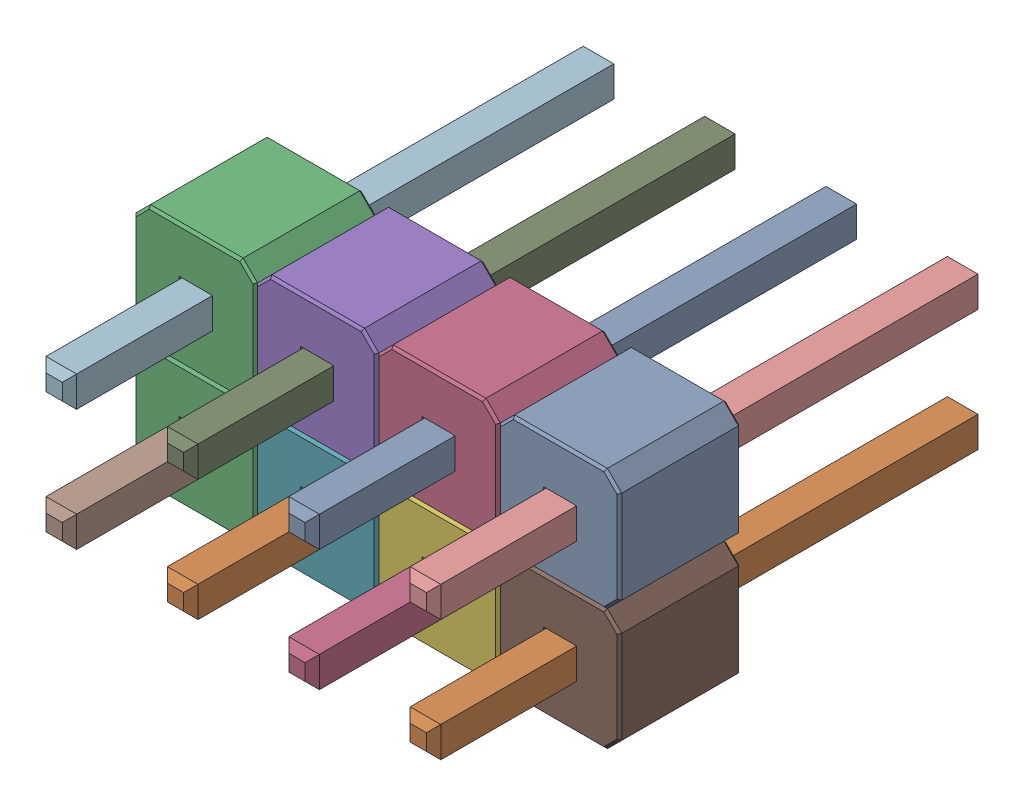
SolidWorks assembly X1_XLR4, configuration Default. Lengths in mm.
Overall size (10.16 5.08 11.54).
17 component instances, 2 part files, 0 mates.
Components (placement in the parent):
- PLD-8-1: PLD-8 [Default] at (47.6251 88.0109 -1.2114) x (1 0 0) z (0 0 -1) size (10.16 5.08 11.54)
  - _______________________-1: _______________________ [Default] at (-2.54 0 -3) size (0.64 0.64 11.54)
  - _______________________-2: _______________________ [Default] at (-5.08 2.54 -3) size (0.64 0.64 11.54)
  - _________-1: _________ [Default] at (-7.6724 2.5342 -0.0112) size (2.54 2.54 2.54)
  - _______________________-3: _______________________ [Default] at (-2.54 2.54 -3) size (0.64 0.64 11.54)
  - _________-2: _________ [Default] at (-5.1324 -0.0058 -0.0112) size (2.54 2.54 2.54)
  - _________-3: _________ [Default] at (-2.5924 2.5342 -0.0112) size (2.54 2.54 2.54)
  - _________-4: _________ [Default] at (-5.1324 2.5342 -0.0112) size (2.54 2.54 2.54)
  - _______________________-4: _______________________ [Default] at (-7.62 2.54 -3) size (0.64 0.64 11.54)
  - _______________________-5: _______________________ [Default] at (-5.08 0 -3) size (0.64 0.64 11.54)
  - _______________________-6: _______________________ [Default] at (0 0 -3) size (0.64 0.64 11.54)
  - _________-5: _________ [Default] at (-0.0524 2.5342 -0.0112) size (2.54 2.54 2.54)
  - _______________________-7: _______________________ [Default] at (-7.62 0 -3) size (0.64 0.64 11.54)
  - _________-6: _________ [Default] at (-0.0524 -0.0058 -0.0112) size (2.54 2.54 2.54)
  - _______________________-8: _______________________ [Default] at (0 2.54 -3) size (0.64 0.64 11.54)
  - _________-7: _________ [Default] at (-7.6724 -0.0058 -0.0112) size (2.54 2.54 2.54)
  - _________-8: _________ [Default] at (-2.5924 -0.0058 -0.0112) size (2.54 2.54 2.54)
